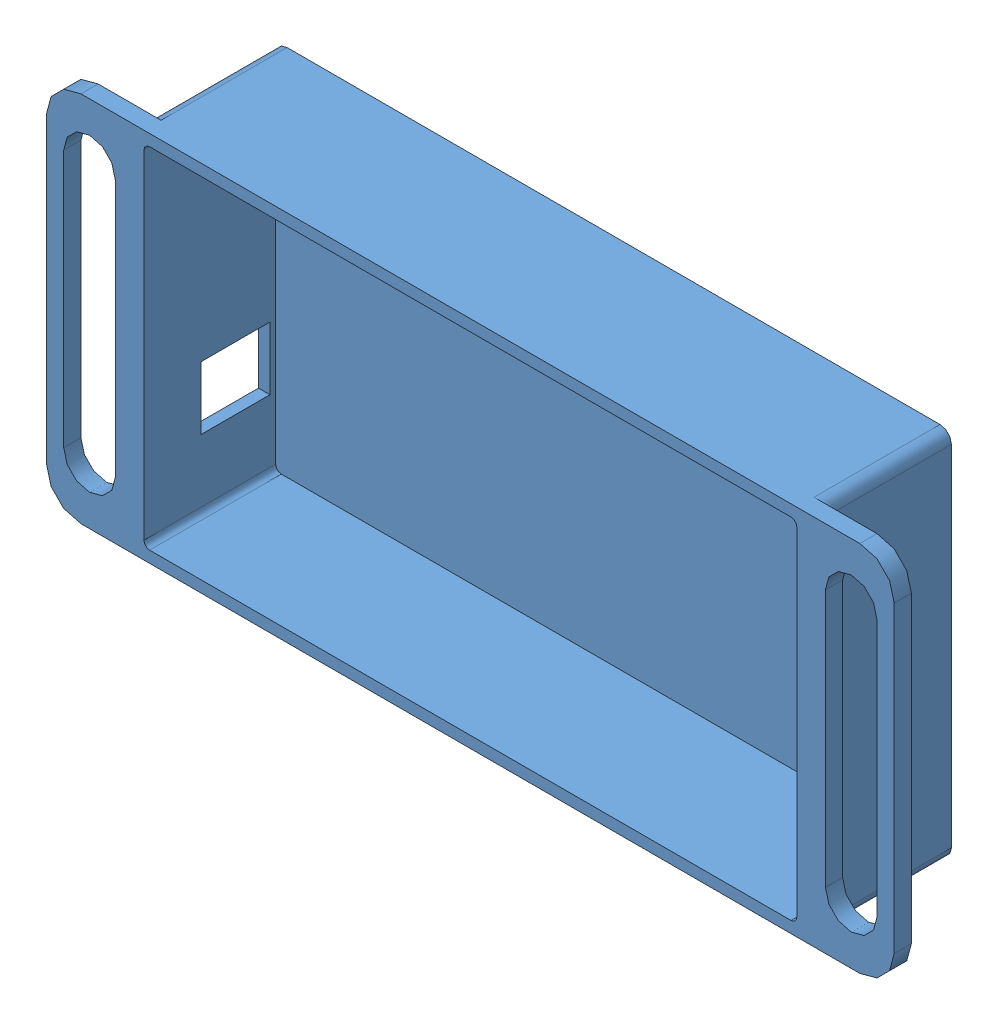
SolidWorks assembly Assem1, configuration Default. Lengths in mm.
Overall size (148 66.62 25).
2 component instances, 2 part files, 2 mates.
Components (placement in the parent):
- ledbandrxtx.wrl-1: ledbandrxtx.wrl [Default] at origin size (113.83 64.08 1.7)
- CaseRX-1: CaseRX [Default] at (131.3603 -91.0434 -0.6713) x (-1 0 0) z (0 0 -1) size (148 65 25)
Mates (geometry in assembly coordinates):
- Parallel1: parallel anti-aligned: plane of CaseRX-1 through (131.3603 -91.0434 -2.6713) normal (0 0 -1); plane of assembly through (0 0 0) normal (0 0 1)
- Parallel2: parallel aligned: plane of CaseRX-1 through (190.3603 -58.5434 -2.6713) normal (0 1 0); plane of assembly through (0 0 0) normal (0 1 0)
